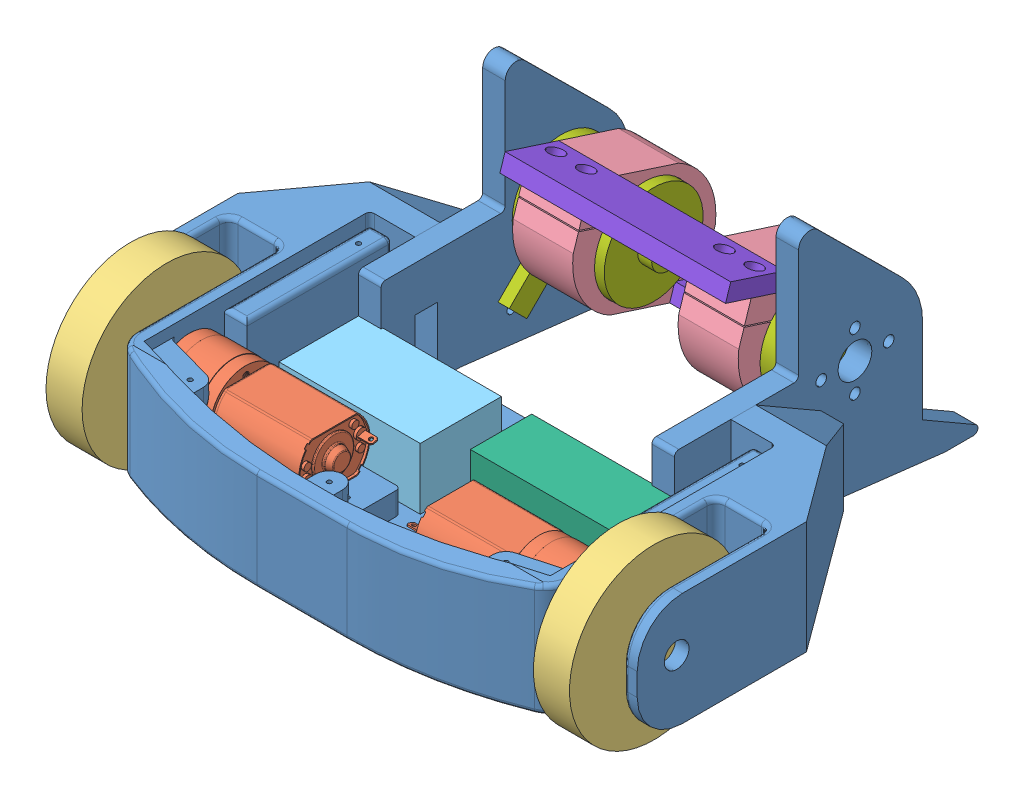
SolidWorks assembly Honey Sickle Assem, configuration Default. Lengths in mm.
Overall size (160.02 73.03 145.76).
19 component instances, 8 part files, 36 mates.
Components (placement in the parent):
- Honey Sickle Master Part-1: Honey Sickle Master Part [Main Body] at origin size (160.02 31.78 101.6)
- Honey Sickle Master Part-2: Honey Sickle Master Part [Right Skid] at (-41.275 0 0) size (6.35 73.03 85.43)
- Honey Sickle Master Part-4: Honey Sickle Master Part [Left Skid] at (41.275 0 0) size (6.35 73.03 85.43)
- Honey Sickle Master Part-5: Honey Sickle Master Part [Cross Support] at (0 1.905 38.1) size (101.6 25.4 6.35)
- 22mm motor.step-1: 22mm motor.step [Default] at (-2.32 23.6675 105.775) x (0 0 1) z (0 1 0) size (20.1 62.94 20)
- 22mm motor.step-2: 22mm motor.step [Default] at (2.32 -45.8925 105.775) x (0 0 1) z (0 -1 0) size (20.1 62.94 20)
- Wheel and Hub-1: Wheel and Hub [Default] at (-68.58 -11.1125 85.725) size (10.16 47.62 47.62)
- Wheel and Hub-2: Wheel and Hub [Default] at (68.58 -11.1125 85.725) x (-1 0 0) z (0 0 -1) size (10.16 47.62 47.62)
- Honey Sickle Master Part-6: Honey Sickle Master Part [Top Plate] at origin size (114.3 3.17 72.39)
- Honey Sickle Master Part-7: Honey Sickle Master Part [Motor Mount Left] at origin size (49.63 25.4 60.66)
- Honey Sickle Master Part-8: Honey Sickle Master Part [Motor Mount Right] at origin size (49.63 25.4 60.66)
- Weapon-1: Weapon [Default] at (-23.2918 -0.0226 -0.0698) x (1 0 0) z (0 0.951454 -0.307791) size (16.92 42 32)
- Weapon-2: Weapon [Default] at (23.2918 -0.0226 -0.0698) x (1 0 0) z (0 0.951454 -0.307791) size (16.92 42 32)
- ESEs-1: ESEs [Default] at (-24.5745 -16.764 61.7538) x (-1 0 0) z (0 0 -1) size (39.75 17.27 22.86)
- 12v Battery-1: 12v Battery [Default] at (30.48 -16.764 58.9597) size (53.34 17.27 17.27)
- D2826 Brushless Motor-1: D2826 Brushless Motor [Default] at (-23.1775 0 0) x (0 -0.707107 -0.707107) z (0 -0.707107 0.707107) size (27.81 29.84 39.31)
- D2826 Brushless Motor-2: D2826 Brushless Motor [Default] at (23.1775 0 0) x (0 0.707107 0.707107) z (0 -0.707107 0.707107) size (27.81 29.84 39.31)
- Weapon Tooth-1: Weapon Tooth [Default] at (0 -19.3066 -15.4344) x (1 0 0) z (0 0.307791 0.951454) size (63.5 4.76 15.88)
- Weapon Tooth-2: Weapon Tooth [Default] at (0 19.3066 15.4344) x (1 0 0) z (0 -0.307791 -0.951454) size (63.5 4.76 15.88)
Mates (geometry in assembly coordinates):
- Coincident1: coincident aligned: plane of Honey Sickle Master Part-1 through (0 0 0) normal (0 1 0)
- Coincident2: coincident aligned: plane of Honey Sickle Master Part-1 through (0 0 0) normal (0 0 1)
- Coincident3: coincident aligned: plane of Honey Sickle Master Part-1 through (0 0 0) normal (1 0 0)
- Coincident4: coincident anti-aligned: plane of Honey Sickle Master Part-1 through (-44.45 38.1 9.525) normal (1 0 0); plane of Honey Sickle Master Part-2 through (-44.45 0 0) normal (-1 0 0)
- Coincident5: coincident aligned: plane of Honey Sickle Master Part-2 through (-41.275 0 0) normal (0 1 0)
- Coincident6: coincident aligned: plane of Honey Sickle Master Part-2 through (-41.275 0 0) normal (0 0 1)
- Coincident14: coincident aligned: plane of Honey Sickle Master Part-5 through (0 1.905 38.1) normal (1 0 0)
- Concentric5: concentric aligned: cylinder of Honey Sickle Master Part-1 through (-80.01 -11.1125 85.725) axis (1 0 0) radius 3.4798; cylinder of 22mm motor.step-1 through (-60.1 -11.1125 85.725) axis (1 0 0) radius 3.48
- Coincident20: coincident anti-aligned: plane of Honey Sickle Master Part-1 through (-57.15 -171.0699 34.925) normal (1 0 0); plane of 22mm motor.step-1 through (-57.15 -11.1125 85.725) normal (-1 0 0)
- Concentric6: concentric anti-aligned: cylinder of 22mm motor.step-1 through (-75.26 -11.1125 85.725) axis (1 0 0) radius 1.975; cylinder of Wheel and Hub-1 through (-63.5 -11.1125 85.725) axis (-1 0 0) radius 2.5
- Width1: width aligned: plane of Wheel and Hub-1 through (-73.66 -11.1125 85.725) normal (-1 0 0); plane of Wheel and Hub-1 through (-63.5 -11.1125 85.725) normal (1 0 0); plane of Honey Sickle Master Part-1 through (-60.96 38.1 100.965) normal (-1 0 0); plane of Honey Sickle Master Part-1 through (-76.2 38.1 55.5625) normal (1 0 0)
- Coincident22: coincident anti-aligned: plane of Honey Sickle Master Part-6 through (0 0 -80.8264) normal (0 -1 0); plane of Honey Sickle Master Part-5 through (-50.8 0 41.275) normal (0 1 0)
- Coincident24: coincident aligned: plane of Honey Sickle Master Part-6 through (0 0 0) normal (1 0 0)
- Coincident25: coincident aligned: plane of Honey Sickle Master Part-6 through (0 0 0) normal (0 0 1)
- Coincident26: coincident anti-aligned: plane of Honey Sickle Master Part-1 through (-80.01 -25.4 111.125) normal (0 1 0); plane of Honey Sickle Master Part-7 through (-39.2684 -25.4 95.5675) normal (0 -1 0)
- Concentric7: concentric aligned: cylinder of 22mm motor.step-1 through (-44.75 -11.1125 85.725) axis (-1 0 0) radius 10; cylinder of Honey Sickle Master Part-7 through (-39.2684 -11.1125 85.725) axis (-1 0 0) radius 9.9568
- Coincident27: coincident anti-aligned: plane of Honey Sickle Master Part-1 through (-57.15 -171.0699 34.925) normal (1 0 0); plane of Honey Sickle Master Part-7 through (-57.15 -11.1125 85.725) normal (-1 0 0)
- Coincident28: coincident anti-aligned: plane of Honey Sickle Master Part-1 through (-80.01 -25.4 111.125) normal (0 1 0); plane of Honey Sickle Master Part-8 through (39.2684 -25.4 95.5675) normal (0 -1 0)
- Coincident29: coincident anti-aligned: plane of Honey Sickle Master Part-1 through (57.15 -171.0699 34.925) normal (-1 0 0); plane of Honey Sickle Master Part-8 through (57.15 -11.1125 85.725) normal (1 0 0)
- Concentric8: concentric aligned: cylinder of 22mm motor.step-2 through (44.75 -11.1125 85.725) axis (1 0 0) radius 10; cylinder of Honey Sickle Master Part-8 through (39.2684 -11.1125 85.725) axis (1 0 0) radius 9.9568
- Parallel1: parallel aligned: plane of 22mm motor.step-1 through (-16.31 -3.4675 85.725) normal (0 1 0); plane of Honey Sickle Master Part-7 through (-7.5184 -19.0119 75.8825) normal (0 1 0)
- Coincident31: coincident: line of Honey Sickle Master Part-1 through (-31.75 0 32.7406) axis (0 0 -1); plane of Weapon-1 through (-31.75 -0.0226 -0.0698) normal (-1 0 0)
- Coincident36: coincident anti-aligned: plane of Honey Sickle Master Part-1 through (-80.01 -25.4 111.125) normal (0 1 0); plane of ESEs-1 through (-24.5745 -25.4 61.7538) normal (0 -1 0)
- Coincident41: coincident anti-aligned: plane of Honey Sickle Master Part-1 through (-80.01 -25.4 111.125) normal (0 1 0); plane of 12v Battery-1 through (30.48 -25.4 58.9597) normal (0 -1 0)
- Coincident42: coincident anti-aligned: plane of Honey Sickle Master Part-1 through (-80.01 -25.4 111.125) normal (0 1 0); plane of ESEs-1 through (-24.5745 -25.4 61.7538) normal (0 -1 0)
- Coincident43: coincident: line of Honey Sickle Master Part-1 through (3.81 0 67.5957) axis (0 0 -1); plane of 12v Battery-1 through (3.81 -8.128 67.5957) normal (-1 0 0)
- Coincident44: coincident: line of Honey Sickle Master Part-1 through (3.81 0 67.5957) axis (1 0 0); plane of 12v Battery-1 through (3.81 -8.128 67.5957) normal (0 0 1)
- Coincident45: coincident: line of Honey Sickle Master Part-1 through (-44.45 0 73.1838) axis (0 0 -1); plane of ESEs-1 through (-44.45 -8.128 73.1838) normal (-1 0 0)
- Coincident46: coincident: line of Honey Sickle Master Part-1 through (-44.45 0 73.1838) axis (1 0 0); plane of ESEs-1 through (-4.699 -8.128 73.1838) normal (0 0 1)
- Coincident47: coincident anti-aligned: plane of Honey Sickle Master Part-2 through (-38.1 0 0) normal (1 0 0); plane of D2826 Brushless Motor-1 through (-38.1 0 0) normal (-1 0 0)
- Concentric11: concentric anti-aligned: cylinder of Honey Sickle Master Part-2 through (-44.45 9.5 0) axis (1 0 0) radius 1.5; cylinder of D2826 Brushless Motor-1 through (-25.4 9.5 0) axis (-1 0 0) radius 1.5
- Concentric12: concentric aligned: cylinder of Weapon-1 through (-14.8336 0 0) axis (-1 0 0) radius 14; cylinder of D2826 Brushless Motor-1 through (-8.255 0 0) axis (-1 0 0) radius 13.9065
- Concentric13: concentric anti-aligned: cylinder of Honey Sickle Master Part-2 through (-44.45 0 0) axis (1 0 0) radius 4.7625; cylinder of D2826 Brushless Motor-1 through (-8.255 0 0) axis (-1 0 0) radius 13.9065
- Coincident51: coincident aligned: plane of Weapon Tooth-1 through (0 -19.3066 -15.4344) normal (1 0 0)
- Coincident52: coincident anti-aligned: plane of Weapon-2 through (31.75 -10.7146 3.389) normal (0 -0.951454 0.307791); plane of Weapon Tooth-1 through (0 -17.0409 -16.1673) normal (0 0.951454 -0.307791)
- Coincident53: coincident anti-aligned: plane of Weapon-1 through (-14.8336 -3.9059 -12.0739) normal (0 -0.307791 -0.951454); plane of Weapon Tooth-1 through (-31.75 -14.5978 -8.6151) normal (0 0.307791 0.951454)
